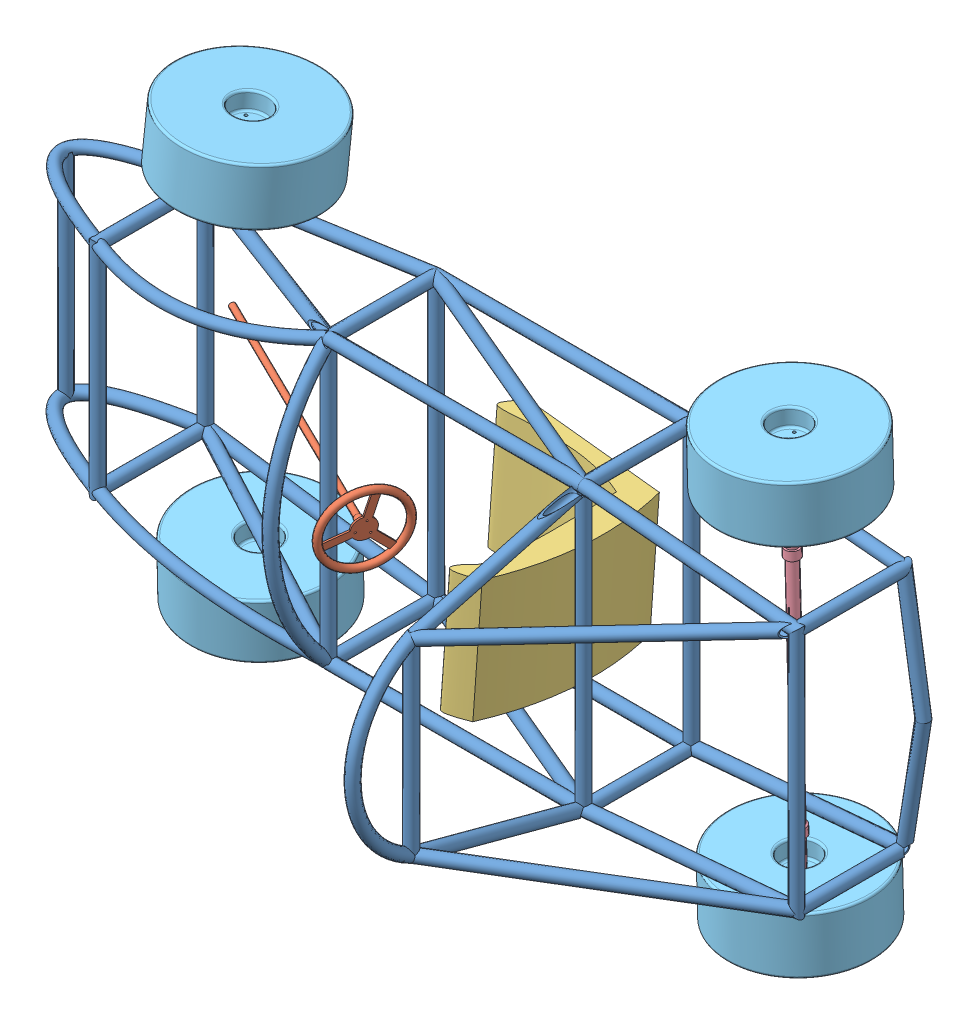
SolidWorks assembly v1 ass, configuration Default. Lengths in mm.
Overall size (2312.05 1268.7 1148.57).
8 component instances, 5 part files, 3 mates.
Components (placement in the parent):
- v1-1: v1 [Default<As Machined>] at (988.5675 1011.3399 1371.042) size (2312.05 813.86 977.95)
- steering column cap-1: steering column cap [Default] at (898.9312 1022.9314 1702.7628) x (-0.195928 -0.963494 0.182458) z (-0.913401 0.11161 -0.391462) size (220 220 715)
- seat-1: seat [Default] at (1355.969 1043.9808 1401.8311) x (-0.995353 0.025537 -0.09285) z (0.029915 0.99849 -0.046067) size (478.91 511.54 340)
- rear axle-1: rear axle [Default] at (1830.561 1271.4272 1441.3999) x (0 -0.999653 -0.026357) z (0.069208 -0.026294 0.997256) size (1100 40 40)
- wheels-1: wheels [Default] at (335.9511 1490.3534 1474.5344) x (0.914706 -0.074155 -0.397257) z (0.058003 0.996933 -0.05254) size (406.4 406.4 160)
- wheels-2: wheels [Default] at (330.2137 583.5269 1425.5271) x (0.986114 -0.051848 0.157772) z (-0.042244 -0.997079 -0.06363) size (406.4 406.4 160)
- wheels-3: wheels [Default] at (1830.561 1460.0126 1446.3722) x (0.999997 0.000069 -0.002629) z (0 0.999653 0.026357) size (406.4 406.4 160)
- wheels-4: wheels [Default] at (1830.561 406.9926 1418.6081) x (0.998067 -0.001638 0.062128) z (0 0.999653 0.026357) size (406.4 406.4 160)
Mates (geometry in assembly coordinates):
- Concentric1: concentric aligned: cylinder of rear axle-1 through (1830.561 1515.0616 1447.8236) axis (0 0.999653 0.026357) radius 15; cylinder of wheels-4 through (1830.561 406.9926 1418.6081) axis (0 0.999653 0.026357) radius 6.5
- Concentric2: concentric aligned: cylinder of rear axle-1 through (1830.561 1515.0616 1447.8236) axis (0 0.999653 0.026357) radius 15; cylinder of wheels-3 through (1830.561 1460.0126 1446.3722) axis (0 0.999653 0.026357) radius 6.5
- Perpendicular1: perpendicular: line of v1-1 through (124.5758 1011.3399 1371.042) axis (1 0 0); cylinder of rear axle-1 through (1830.561 1515.0616 1447.8236) axis (0 0.999653 0.026357) radius 15
